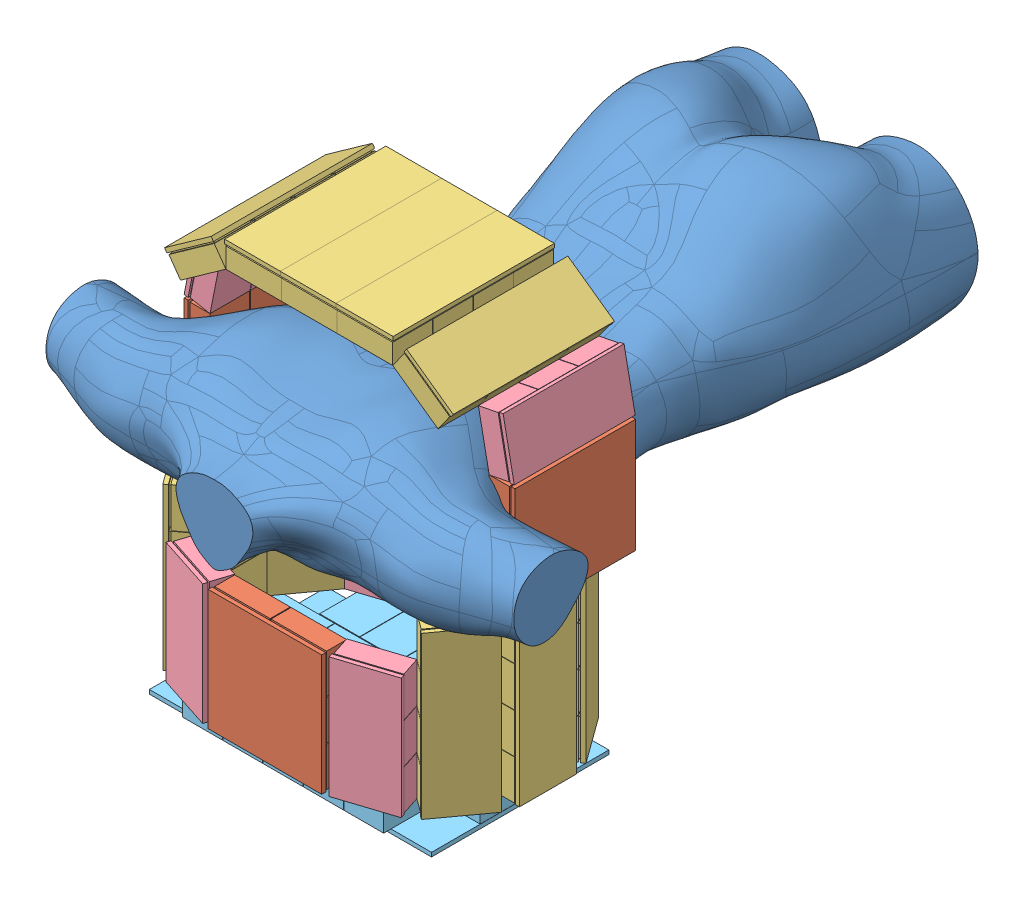
SolidWorks assembly BODYdetector3, configuration Default. Lengths in mm.
Overall size (637.83 509.15 817.55).
28 component instances, 5 part files, 4 mates.
Components (placement in the parent):
- woman body-1: woman body [Default] at (325.4407 484.4544 221.086) size (637.83 301.02 817.55)
- Detector1n3_3-1: Detector1n3_3 [Default] at (49.8582 665.158 553.2219) x (1 0 0) z (0 -1 0) size (495.24 340.33 231)
  - Detector1n2_changed-1: Detector1n2_changed [Default] at (214.6875 32.8122 259.0633) size (495.24 340.33 200.99)
    - top_bottomDetector2-1: top_bottomDetector2 [Default] at (5.3043 60.2155 74.3483) size (141 32 149.74)
    - CshapedDetector2-1: CshapedDetector2 [Default] at (104.3454 -76.5763 -85.899) x (0.951057 0.309017 0) z (0 0 1) size (177.89 270.84 200)
      - 1Detector-2: 1Detector [Default] at (173.0714 153.2337 184.2598) x (0.809017 0.587785 0) z (0 0 1) size (71 32 200)
      - 1Detector-4: 1Detector [Default] at (223.2683 222.3237 184.2598) x (0.309017 0.951057 0) z (0 0 1) size (71 32 200)
      - 1Detector-5: 1Detector [Default] at (223.2683 307.7237 184.2598) x (-0.309017 0.951057 0) z (0 0 1) size (71 32 200)
      - 1Detector_3modules-1: 1Detector_3modules [Default] at (91.8512 126.8436 209.2598) size (71 32 150)
      - 1Detector_3modules-2: 1Detector_3modules [Default] at (173.0714 376.8138 209.2598) x (-0.809017 0.587785 0) z (0 0 1) size (71 32 150)
    - CshapedDetector2-2: CshapedDetector2 [Default] at (-23.7368 484.2959 -85.899) x (-0.951057 -0.309017 0) z (0 0 1) size (177.89 270.84 200)
      - 1Detector-2: 1Detector [Default] at (173.0714 153.2337 184.2598) x (0.809017 0.587785 0) z (0 0 1) size (71 32 200)
      - 1Detector-4: 1Detector [Default] at (223.2683 222.3237 184.2598) x (0.309017 0.951057 0) z (0 0 1) size (71 32 200)
      - 1Detector-5: 1Detector [Default] at (223.2683 307.7237 184.2598) x (-0.309017 0.951057 0) z (0 0 1) size (71 32 200)
      - 1Detector_3modules-1: 1Detector_3modules [Default] at (91.8512 126.8436 209.2598) size (71 32 150)
      - 1Detector_3modules-2: 1Detector_3modules [Default] at (173.0714 376.8138 209.2598) x (-0.809017 0.587785 0) z (0 0 1) size (71 32 150)
    - top_bottomDetector2-2: top_bottomDetector2 [Default] at (75.3043 347.5042 74.3483) x (-1 0 0) z (0 0 1) size (141 32 149.74)
  - Detector3-1: Detector3 [Default] at (255.9219 239.5761 488.4241) x (0 -1 0) z (1 0 0) size (239.5 31 350)
- Detector_posterial2-1: Detector_posterial2 [Default] at (218.3959 771.2045 927.1336) x (1 0 0) z (0 0 -1) size (410.4 279.65 200.24)
  - 1Detector-1: 1Detector [Default] at (83.9721 85.3161 150.6758) size (71 32 200)
  - 1Detector-2: 1Detector [Default] at (152.9721 85.3161 150.6758) size (71 32 200)
  - 1Detector-3: 1Detector [Default] at (14.9721 85.3161 150.6758) size (71 32 200)
  - 1Detector-4: 1Detector [Default] at (-66.1879 111.2254 150.6758) x (0.815027 -0.579423 0) z (0 0 1) size (71 32 200)
  - 1Detector-5: 1Detector [Default] at (234.132 111.2254 150.6758) x (0.815027 0.579423 0) z (0 0 1) size (71 32 200)
  - 1Detector_3modules-1: 1Detector_3modules [Default] at (-113.8805 184.8905 175.6758) x (0.19509 -0.980785 0) z (0 0 1) size (71 32 150)
  - 1Detector_3modules-2: 1Detector_3modules [Default] at (281.8247 184.8905 175.6758) x (0.19509 0.980785 0) z (0 0 1) size (71 32 150)
  - top_bottomDetector2-1: top_bottomDetector2 [Default] at (289.1701 259.4705 125.9183) x (0 1 0) z (0 0 1) size (141 32 149.74)
  - top_bottomDetector2-2: top_bottomDetector2 [Default] at (-121.226 329.4705 125.9183) x (0 -1 0) z (0 0 1) size (141 32 149.74)
Mates (geometry in assembly coordinates):
- Coincident2: coincident anti-aligned: line of ? through (525.8671 534.1982 703.9257) axis (0 0 1); line of ? through (525.8671 534.1982 753.4257) axis (0 0 -1)
- Coincident3: coincident: point of ?; point of ?
- Parallel1: parallel aligned: plane of Detector1n3_3-1/Detector1n2_changed-1/CshapedDetector2-1/1Detector-4 through (512.5301 307.734 789.8939) normal (1 0 0); plane of Detector_posterial2-1/top_bottomDetector2-1 through (507.5661 511.734 801.2154) normal (1 0 0)
- Coincident5: coincident anti-aligned: line of Detector1n3_3-1/Detector1n2_changed-1/CshapedDetector2-2/1Detector-4 through (129.1699 407.234 755.3939) axis (0 0 1); line of Detector_posterial2-1/top_bottomDetector2-2 through (129.1699 407.234 825.9578) axis (0 0 -1)
